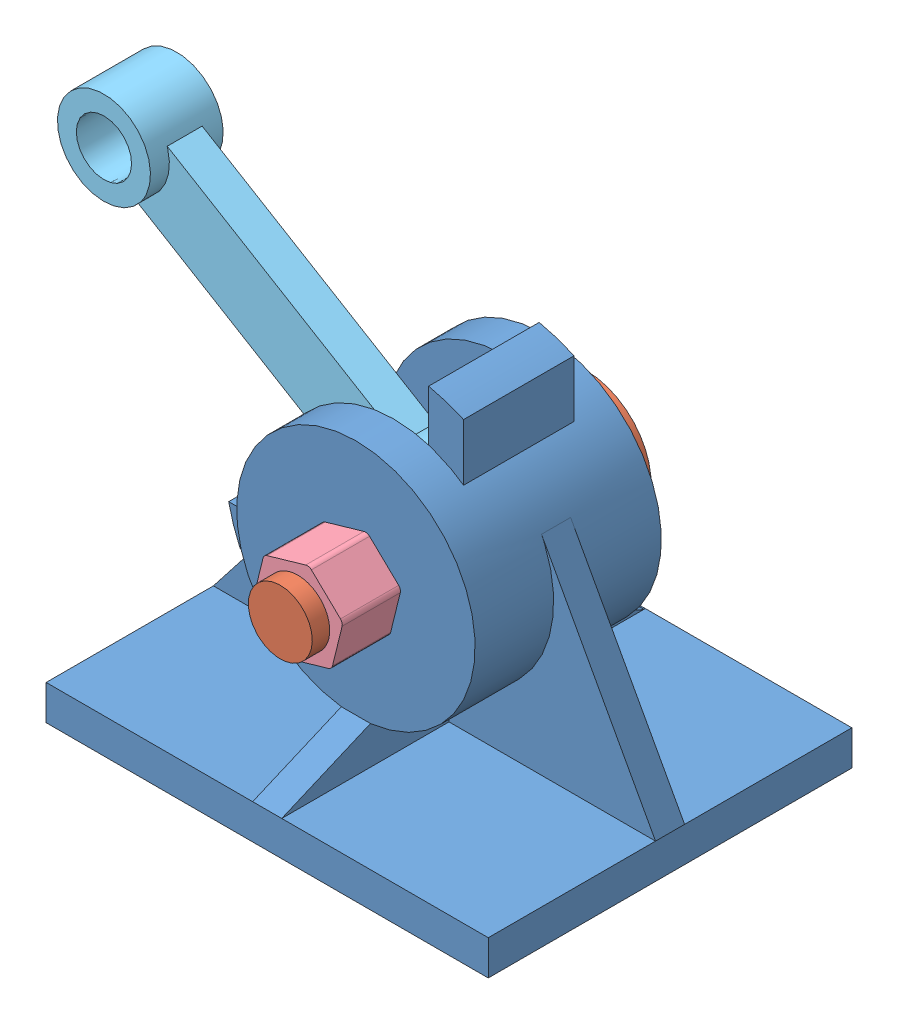
SolidWorks assembly rocking arm, configuration Default. Lengths in mm.
Overall size (209.21 158.94 125).
5 component instances, 5 part files, 5 mates.
Components (placement in the parent):
- base-1: base [Default] at (-111.5614 -3.6549 -82.8487) size (152 122.45 125)
- pen-1: pen [Default] at (-35.5614 62.055 -67.3487) x (0 0 1) z (-0.14137 -0.989957 0) size (105 45 45)
- boly-1: boly [Default] at (-35.5614 62.055 -39.3487) size (35 35 36)
- nut-1: nut [Default] at (-35.5614 62.055 11.6513) size (30.61 30.91 20)
- pl-1: pl [Default] at (-142.6871 126.4683 -39.3487) x (0.857006 -0.515306 0) z (0 0 1) size (165 48 36)
Mates (geometry in assembly coordinates):
- Hinge1: hinge aligned: cylinder of pl-1 through (-35.5614 62.055 -3.3487) axis (0 0 -1) radius 17.5; cylinder of pl-1 through (-35.5614 62.055 -3.3487) axis (0 0 -1) radius 14; plane of Part2-1 through (-142.0512 127.5143 -39.3487) normal (0 0 -1); plane of Part2-1 through (-35.5614 62.055 -39.3487) normal (0 0 -1)
- Hinge3: hinge anti-aligned: cylinder of Part1-1 through (-35.5614 62.055 37.6513) axis (0 0 1) radius 14; cylinder of Part1-1 through (-35.5614 62.055 -52.3487) axis (0 0 1) radius 14; plane of Part11-1 through (-57.8354 65.2358 -52.3487) normal (0 0 1); plane of Part11-1 through (-35.5614 62.055 -52.3487) normal (0 0 -1)
- Hinge4: hinge anti-aligned: cylinder of Part2-1 through (-35.5614 62.055 -3.3487) axis (0 0 -1) radius 14; cylinder of Part2-1 through (-35.5614 62.055 -52.3487) axis (0 0 1) radius 14; plane of Part11-1 through (-35.5614 62.055 -39.3487) normal (0 0 -1); plane of Part11-1 through (-35.5614 62.055 -39.3487) normal (0 0 1)
- Hinge5: hinge anti-aligned: cylinder of Part3-1 through (-35.5614 62.055 31.6513) axis (0 0 -1) radius 11; cylinder of Part3-1 through (-35.5614 62.055 11.6513) axis (0 0 -1) radius 11; plane of Part11-1 through (-35.5614 62.055 11.6513) normal (0 0 -1); plane of Part11-1 through (-35.5614 62.055 11.6513) normal (0 0 1)
- LimitAngle1: limit planar angle = 0.541365 rad aligned: plane of Part4-1 through (-142.6871 126.4683 -39.3487) normal (0.515306 0.857006 0); plane of Part11-1 through (-74.7659 50.055 -1.3487) normal (0 1 0)
